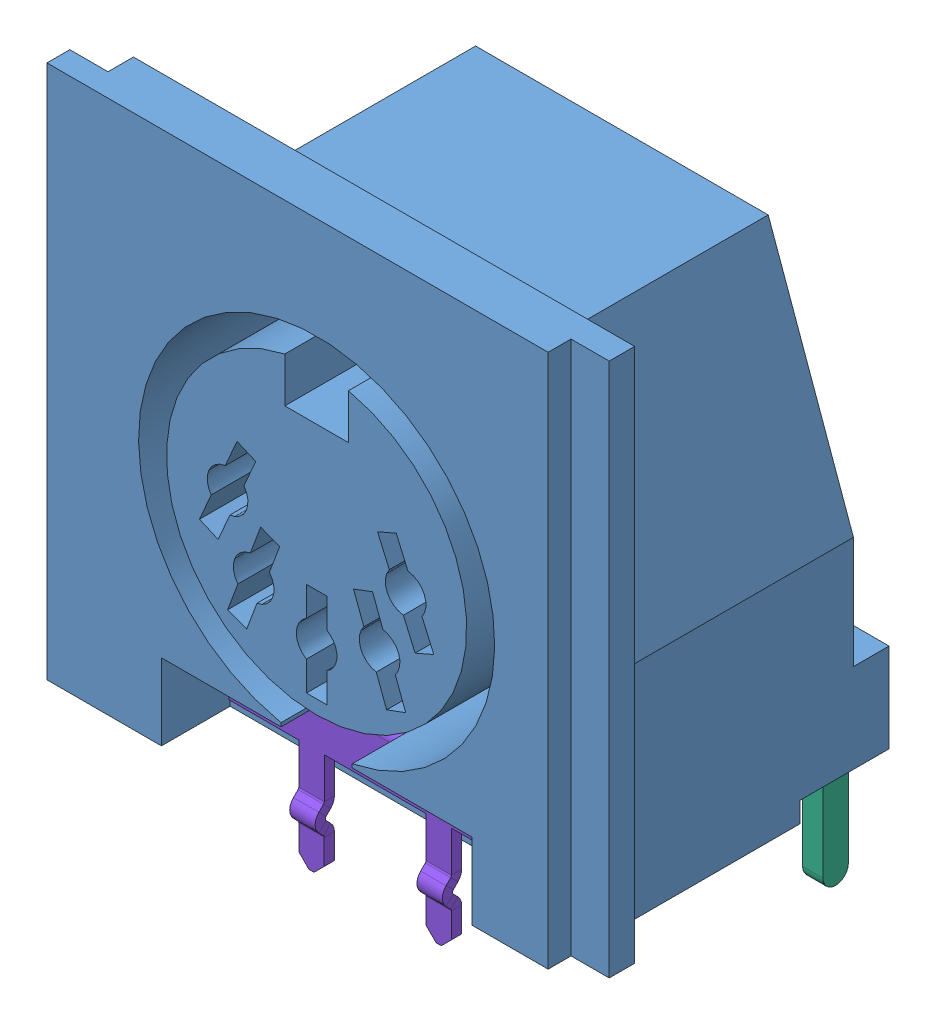
SolidWorks assembly 5-PIN-DIN-RA-PCB-NEW, configuration Výchozí. Lengths in mm.
Overall size (21.2 25 29.3).
8 component instances, 8 part files, 20 mates.
Components (placement in the parent):
- DIN5_PCB_DELTRON_BODY-1: DIN5_PCB_DELTRON_BODY [Výchozí] at origin size (21.2 21 13.6)
- DIN5_PCB_DELTRON_PIN2-1: DIN5_PCB_DELTRON_PIN2 [Výchozí] at (0 -4 -12.5) size (0.8 12.35 11.9)
- DIN5_PCB_DELTRON_PIN5-1: DIN5_PCB_DELTRON_PIN5 [Výchozí] at (0 0 -15.5) size (3.95 13.4 13.8)
- DIN5_PCB_DELTRON_PIN3-1: DIN5_PCB_DELTRON_PIN3 [Výchozí] at (-7.5 -4 -13.6) x (-1 0 0) z (0 0 -1) size (5.5 15.86 11.9)
- DIN5_PCB_DELTRON_PIN4-1: DIN5_PCB_DELTRON_PIN4 [Výchozí] at (0 0 -15.5) x (-1 0 0) z (0 0 -1) size (3.95 13.4 27.6)
- DIN5_PCB_DELTRON_PIN1-1: DIN5_PCB_DELTRON_PIN1 [Výchozí] at (7.5 -4 -13.6) size (5.5 15.86 23.8)
- DIN5_PCB_DELTRON_FIX-2: DIN5_PCB_DELTRON_FIX [Výchozí] at (-6.7271 43.7401 -13.4) size (10.85 8.3 1.4)
- DIN5_PCB_DELTRON_SHIELD-1: DIN5_PCB_DELTRON_SHIELD [Výchozí] at (0 -3.6 -2.3) size (11.5 7.46 6.61)
Mates (geometry in assembly coordinates):
- Sjednocená3: coincident anti-aligned: plane of DIN5_PCB_DELTRON_BODY-1 through (0.4 8.35 0) normal (-1 0 0); plane of DIN5_PCB_DELTRON_PIN2-1 through (0.4 -3.5 -12.5) normal (1 0 0)
- Sjednocená4: coincident anti-aligned: plane of DIN5_PCB_DELTRON_BODY-1 through (0.4 8.35 0) normal (0 -1 0); plane of DIN5_PCB_DELTRON_PIN2-1 through (0.4 8.35 -12) normal (0 1 0)
- Sjednocená8: coincident anti-aligned: plane of DIN5_PCB_DELTRON_BODY-1 through (-1.4501 9.1165 0) normal (-0.351514 -0.936182 0); plane of DIN5_PCB_DELTRON_PIN5-1 through (-1.4501 9.1165 -1.7) normal (0.351514 0.936182 0)
- Sjednocená9: coincident anti-aligned: plane of DIN5_PCB_DELTRON_BODY-1 through (-2.199 9.3977 0) normal (0.936182 -0.351514 0); plane of DIN5_PCB_DELTRON_PIN5-1 through (-5.3234 1.0766 -1.7) normal (-0.936182 0.351514 0)
- Sjednocená10: coincident anti-aligned: plane of DIN5_PCB_DELTRON_BODY-1 through (9.1 4.3 -12) normal (0 0 -1); plane of DIN5_PCB_DELTRON_PIN5-1 through (-6.3063 6.9876 -12) normal (0 0 1)
- Sjednocená11: coincident anti-aligned: plane of DIN5_PCB_DELTRON_BODY-1 through (-2.3955 11.5371 0) normal (-0.398726 -0.91707 0); plane of DIN5_PCB_DELTRON_PIN3-1 through (-2.3955 11.5371 -1.7) normal (0.398726 0.91707 0)
- Sjednocená12: coincident anti-aligned: plane of DIN5_PCB_DELTRON_BODY-1 through (-3.1292 11.8561 0) normal (0.91707 -0.398726 0); plane of DIN5_PCB_DELTRON_PIN3-1 through (-3.1292 11.8561 -1.7) normal (-0.91707 0.398726 0)
- Sjednocená13: coincident anti-aligned: plane of DIN5_PCB_DELTRON_BODY-1 through (9.1 4.3 -12) normal (0 0 -1); plane of DIN5_PCB_DELTRON_PIN3-1 through (-7.5 -4 -12) normal (0 0 1)
- Sjednocená14: coincident anti-aligned: plane of DIN5_PCB_DELTRON_BODY-1 through (2.199 9.3977 0) normal (0.351514 -0.936182 0); plane of DIN5_PCB_DELTRON_PIN4-1 through (1.4501 9.1165 -1.7) normal (-0.351514 0.936182 0)
- Sjednocená17: coincident anti-aligned: plane of DIN5_PCB_DELTRON_BODY-1 through (2.199 9.3977 0) normal (-0.936182 -0.351514 0); plane of DIN5_PCB_DELTRON_PIN4-1 through (5.3234 1.0766 -1.7) normal (0.936182 0.351514 0)
- Sjednocená18: coincident anti-aligned: plane of DIN5_PCB_DELTRON_BODY-1 through (9.1 4.3 -12) normal (0 0 -1); plane of DIN5_PCB_DELTRON_PIN4-1 through (6.3063 6.9876 -12) normal (0 0 1)
- Sjednocená19: coincident anti-aligned: plane of DIN5_PCB_DELTRON_BODY-1 through (3.1292 11.8561 0) normal (-0.91707 -0.398726 0); plane of DIN5_PCB_DELTRON_PIN1-1 through (3.1292 11.8561 -1.7) normal (0.91707 0.398726 0)
- Sjednocená20: coincident anti-aligned: plane of DIN5_PCB_DELTRON_BODY-1 through (2.3955 11.5371 0) normal (0.398726 -0.91707 0); plane of DIN5_PCB_DELTRON_PIN1-1 through (2.3955 11.5371 -1.7) normal (-0.398726 0.91707 0)
- Sjednocená21: coincident anti-aligned: plane of DIN5_PCB_DELTRON_BODY-1 through (9.1 4.3 -12) normal (0 0 -1); plane of DIN5_PCB_DELTRON_PIN1-1 through (7.5 -4 -12) normal (0 0 1)
- Soustředná2: concentric anti-aligned: cylinder of DIN5_PCB_DELTRON_BODY-1 through (0 10 -13.4) axis (0 0 1) radius 0.8; cylinder of DIN5_PCB_DELTRON_FIX-2 through (0 10 -12) axis (0 0 -1) radius 0.8
- Rovnoběžná2: parallel aligned: plane of DIN5_PCB_DELTRON_BODY-1 through (5.75 18 20.0666) normal (0 1 0); plane of DIN5_PCB_DELTRON_FIX-2 through (-1.7 13.8 -12) normal (0 1 0)
- Sjednocená25: coincident anti-aligned: plane of DIN5_PCB_DELTRON_BODY-1 through (9.1 4.3 -12) normal (0 0 -1); plane of DIN5_PCB_DELTRON_FIX-2 through (-6.7271 43.7401 -12) normal (0 0 1)
- Sjednocená30: coincident anti-aligned: plane of DIN5_PCB_DELTRON_BODY-1 through (-6.1 2.4 -20.8147) normal (0 1 0); plane of DIN5_PCB_DELTRON_SHIELD-1 through (5.75 2.4 -2.3) normal (0 -1 0)
- Sjednocená31: coincident anti-aligned: plane of DIN5_PCB_DELTRON_BODY-1 through (0 0 -2.7) normal (0 0 1); plane of DIN5_PCB_DELTRON_SHIELD-1 through (5.75 -3.6 -2.7) normal (0 0 -1)
- Vzdálenost4: distance = 0.35 mm anti-aligned: plane of DIN5_PCB_DELTRON_SHIELD-1 through (5.75 2.3 -2.8) normal (1 0 0); plane of DIN5_PCB_DELTRON_BODY-1 through (6.1 0 -2.7) normal (-1 0 0)
